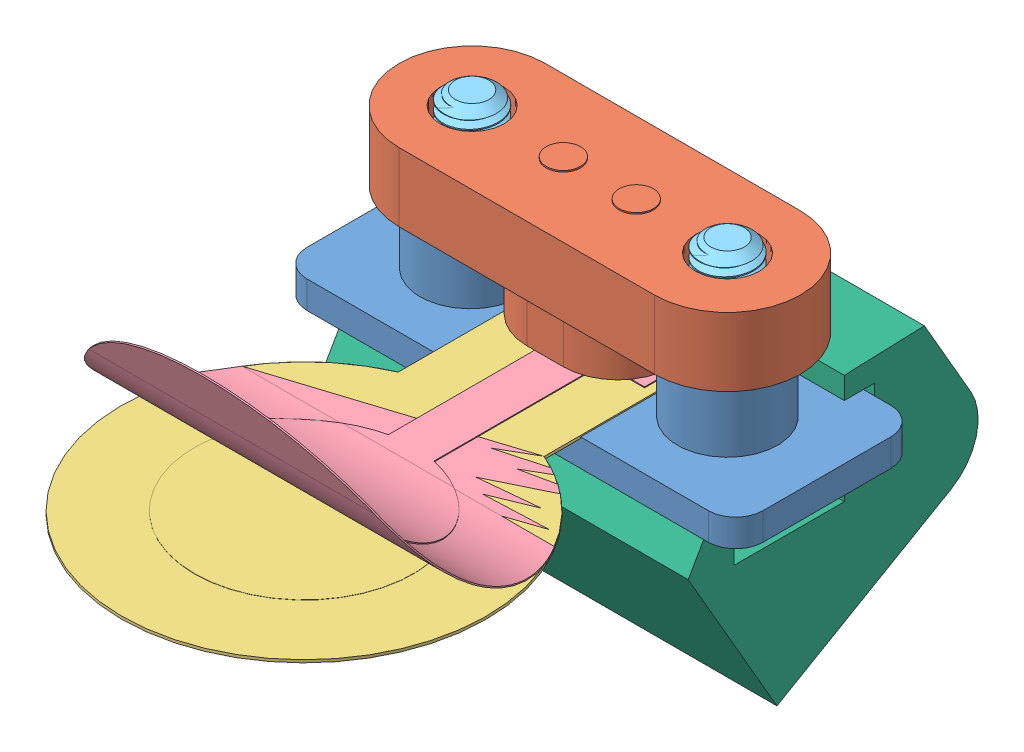
SolidWorks assembly electrode-assembly, configuration Default. Lengths in mm.
Overall size (25 21.42 33.61).
7 component instances, 6 part files, 13 mates.
Components (placement in the parent):
- electrode-3Dprinted-adapter-1: electrode-3Dprinted-adapter [Default] at (-18.0083 -3.1612 9.7821) size (25 5.5 10)
- MilliMax_PogoPin_858-10-002-30-001101-1: MilliMax_PogoPin_858-10-002-30-001101 [Default] at (-17.9573 6.098 9.7821) x (-1 0 0) z (0 0 1) size (22 8.98 8)
- electrode-1: electrode [Default] at (229.448 -1.7362 44.5058) x (0 0 -1) z (1 0 0) size (29.17 0.16 20) (hidden)
- electrode-bent-1: electrode-bent [Default] at (229.448 -1.7362 44.5058) x (0 0 -1) z (1 0 0) size (24.73 9.28 20.06)
- 93640A125_Nylon Plastic Socket Head Screw-1: 93640A125_Nylon Plastic Socket Head Screw [93640A125] at (-10.9583 6.8388 9.7821) x (0 0 -1) z (0 1 0) size (4.6 4.6 13.01)
- 93640A125_Nylon Plastic Socket Head Screw-2: 93640A125_Nylon Plastic Socket Head Screw [93640A125] at (-24.9583 6.8388 9.7821) x (0 0 -1) z (0 1 0) size (4.6 4.6 13.01)
- electrode-holder-2: electrode-holder [Default] at (13.7917 -4.2307 26.3837) x (1 0 0) z (0 0.866025 0.5) size (20 14 10.84)
Mates (geometry in assembly coordinates):
- Distance1: distance = 8.5 mm aligned: plane of LIG_EMG_v2-1 through (-14.0083 -1.5862 44.5058) normal (1 0 0); plane of PogoPin_M3Screw_Adapter-1 through (-5.5083 -1.6612 6.2821) normal (1 0 0)
- Parallel2: parallel aligned: plane of MilliMax_PogoPin_858-10-002-30-001101-1 through (-10.9583 2.3388 5.7816) normal (0 0 -1); plane of LIG_EMG_v2-1 through (229.448 -1.5862 6.7793) normal (0 0 -1)
- Coincident7: coincident anti-aligned: plane of PogoPin_M3Screw_Adapter-1 through (-10.9583 2.3388 9.7821) normal (0 1 0); plane of MilliMax_PogoPin_858-10-002-30-001101-1 through (-10.9583 2.3388 9.7821) normal (0 -1 0)
- Concentric2: concentric aligned: cylinder of PogoPin_M3Screw_Adapter-1 through (-10.9583 -1.6612 9.7821) axis (0 -1 0) radius 2.1; cylinder of MilliMax_PogoPin_858-10-002-30-001101-1 through (-10.9583 6.1742 9.7821) axis (0 -1 0) radius 1.75
- Distance4: distance = 6 mm: plane of MilliMax_PogoPin_858-10-002-30-001101-1 through (-16.9573 -0.8108 12.7793) normal (0 0 1); line of LIG_EMG_v2-1 through (-14.0083 -1.5862 6.7793) axis (-1 0 0)
- Coincident8: coincident anti-aligned: plane of PogoPin_M3Screw_Adapter-1 through (-29.0083 -1.6612 13.2821) normal (0 1 0); plane of LIG_EMG_v2_bent-1 through (229.448 -1.6612 44.5058) normal (0 -1 0)
- Coincident10: coincident aligned: line of LIG_EMG_v2-1 through (-14.0083 -1.5862 6.7793) axis (-1 0 0); line of LIG_EMG_v2_bent-1 through (-14.0083 -1.5862 6.7793) axis (-1 0 0)
- Coincident11: coincident aligned: line of LIG_EMG_v2-1 through (-22.0083 -1.5862 6.7793) axis (0 0 1); line of LIG_EMG_v2_bent-1 through (-22.0083 -1.5862 6.7793) axis (0 0 1)
- Coincident12: coincident anti-aligned: plane of PogoPin_M3Screw_Adapter-1 through (-29.0083 -3.1612 13.2821) normal (0 -1 0); plane of 93640A125_Nylon Plastic Socket Head Screw-1 through (-10.9583 -3.1612 9.7821) normal (0 1 0)
- Concentric3: concentric anti-aligned: cylinder of PogoPin_M3Screw_Adapter-1 through (-10.9583 -1.6612 9.7821) axis (0 -1 0) radius 2.1; cylinder of 93640A125_Nylon Plastic Socket Head Screw-1 through (-10.9583 -5.9612 9.7821) axis (0 1 0) radius 2.3
- Coincident15: coincident anti-aligned: plane of 93640A125_Nylon Plastic Socket Head Screw-1 through (-10.9583 -5.9612 9.7821) normal (0 -1 0); plane of electrode-holder-2 through (-8.0083 -5.9612 6.3296) normal (0 1 0)
- Distance5: distance = 0.1 mm anti-aligned: plane of PogoPin_M3Screw_Adapter-1 through (-29.0083 -1.6612 4.7821) normal (0 0 -1); plane of electrode-holder-2 through (-8.0083 -1.1612 4.6821) normal (0 0 1)
- Distance6: distance = 2.5 mm aligned: plane of electrode-holder-2 through (-8.0083 -5.7111 1.9946) normal (1 0 0); plane of PogoPin_M3Screw_Adapter-1 through (-5.5083 -1.6612 6.2821) normal (1 0 0)
